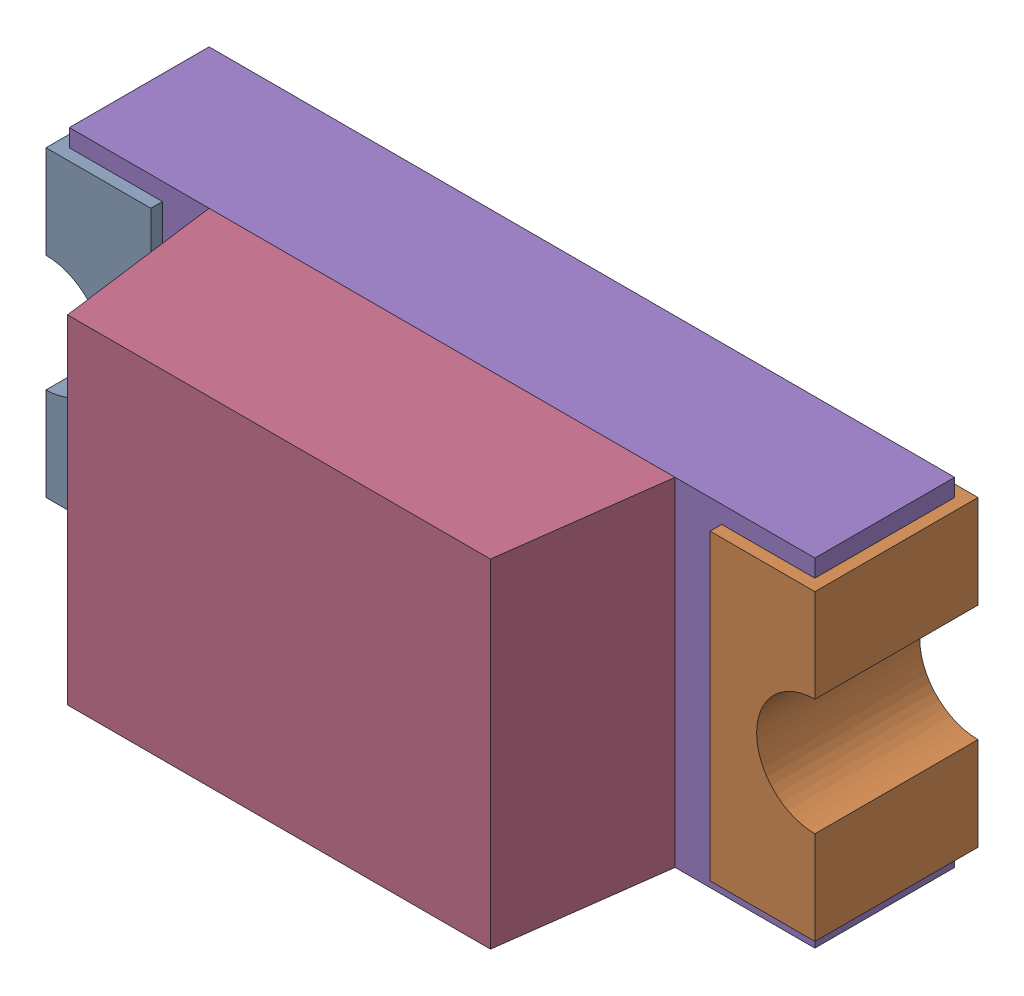
SolidWorks assembly P2, configuration Standard. Lengths in mm.
Overall size (1.65 0.73 0.68).
6 component instances, 5 part files, 0 mates.
Components (placement in the parent):
- P2-subassembly-1-1: P2-subassembly-1 [Standard] at (14.7501 -17.8999 0) x (0 1 0) z (0 0 1) size (0.72 1.65 0.68)
  - User Library-LED SMD0603-1: User Library-LED SMD0603 [Standard] at origin size (0.65 0.28 0.35)
  - User Library-LED SMD0603-1-1: User Library-LED SMD0603-1 [Standard] at origin size (0.65 0.28 0.35)
  - User Library-LED SMD0603-2-1: User Library-LED SMD0603-2 [Standard] at origin size (0.15 0.16 0.07)
  - User Library-LED SMD0603-3-1: User Library-LED SMD0603-3 [Standard] at origin size (0.72 1 0.35)
  - User Library-LED SMD0603-4-1: User Library-LED SMD0603-4 [Standard] at origin size (0.72 1.6 0.3)
